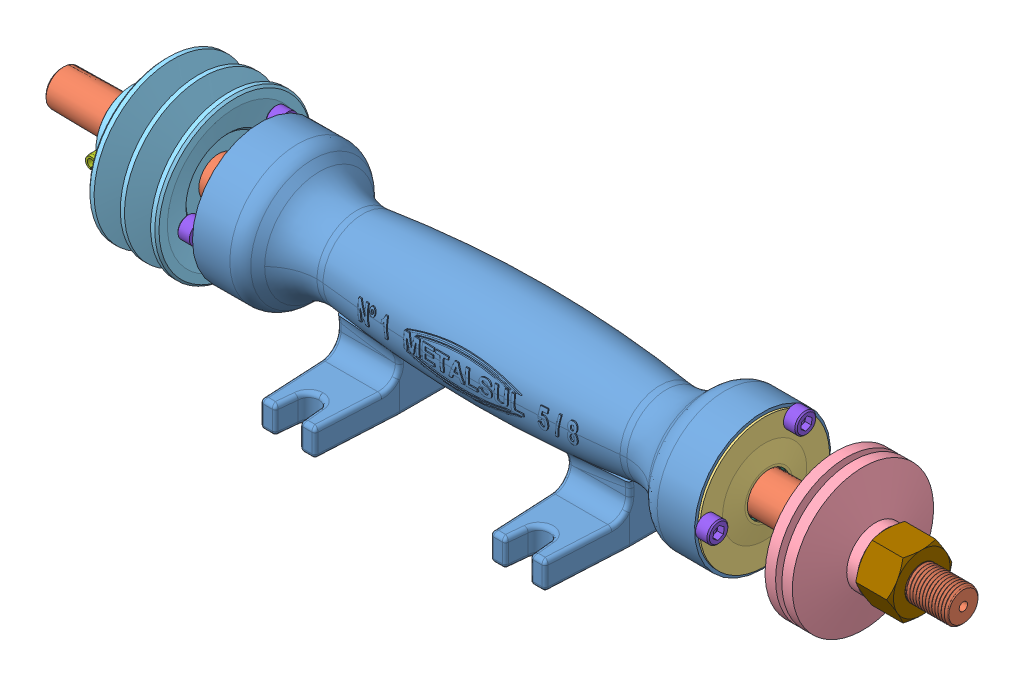
SolidWorks assembly Eixo Serra Circular 5-8 N1, configuration Valor predeterminado. Lengths in mm.
Overall size (431.24 80.12 104.06).
17 component instances, 9 part files, 0 mates.
Components (placement in the parent):
- Base Principal-1: Base Principal [Valor predeterminado] at origin size (240 75.12 104.06)
- Eixo Principal-1: Eixo Principal [Valor predeterminado] at (9 0 0) size (431.24 28 28)
- Tampa Rolamento-1: Tampa Rolamento [Valor predeterminado] at (121.5 0 0) x (0 0 1) z (-1 0 0) size (62 62 3)
- Tampa Rolamento-2: Tampa Rolamento [Valor predeterminado] at (-121.5 0 0) x (0 0 1) z (1 0 0) size (62 62 3)
- Suporte Principal-1: Suporte Principal [Valor predeterminado] at (152 0 0) size (16 67.5 67.5)
- Suporte Principal-2: Suporte Principal [Valor predeterminado] at (171 0 0) x (-1 0 0) z (0 0 -1) size (16 67.5 67.5)
- Polia Correa Dupla-1: Polia Correa Dupla [Valor predeterminado] at (-157 0 0) size (50 75 75)
- angular contact ball bearing_68_skf_SKF - 7204 BE - 10,DE,AC,10_68-1: angular contact ball bearing_68_skf_SKF - 7204 BE - 10,DE,AC,10_68 [Valor predeterminado] at (113 0 0) size (14 47 47)
- angular contact ball bearing_68_skf_SKF - 7204 BE - 10,DE,AC,10_68-2: angular contact ball bearing_68_skf_SKF - 7204 BE - 10,DE,AC,10_68 [Valor predeterminado] at (-113 0 0) size (14 47 47)
- spring pin slotted_hd_din_Spring Pin ISO 8752 - 6 x 50 - N - St-1: spring pin slotted_hd_din_Spring Pin ISO 8752 - 6 x 50 - N - St [Valor predeterminado] at (-176 0 25) x (0 0 -1) z (0 -1 0) size (50 6 5.99)
- socket head cap screw_am_B18.3.1M - 6 x 1.0 x 16 Hex SHCS -- 16SHX-1: socket head cap screw_am_B18.3.1M - 6 x 1.0 x 16 Hex SHCS -- 16SHX [Valor predeterminado] at (127 24.2487 -14) x (-1 0 0) z (0 0.924225 0.381849) size (22 10 10)
- socket head cap screw_am_B18.3.1M - 6 x 1.0 x 16 Hex SHCS -- 16SHX-2: socket head cap screw_am_B18.3.1M - 6 x 1.0 x 16 Hex SHCS -- 16SHX [Valor predeterminado] at (127 0 28) x (-1 0 0) z (0 0.924225 0.381849) size (22 10 10)
- socket head cap screw_am_B18.3.1M - 6 x 1.0 x 16 Hex SHCS -- 16SHX-3: socket head cap screw_am_B18.3.1M - 6 x 1.0 x 16 Hex SHCS -- 16SHX [Valor predeterminado] at (127 -24.2487 -14) x (-1 0 0) z (0 0.924225 0.381849) size (22 10 10)
- socket head cap screw_am_B18.3.1M - 6 x 1.0 x 16 Hex SHCS -- 16SHX-4: socket head cap screw_am_B18.3.1M - 6 x 1.0 x 16 Hex SHCS -- 16SHX [Valor predeterminado] at (-127 24.2487 -14) size (22 10 10)
- socket head cap screw_am_B18.3.1M - 6 x 1.0 x 16 Hex SHCS -- 16SHX-5: socket head cap screw_am_B18.3.1M - 6 x 1.0 x 16 Hex SHCS -- 16SHX [Valor predeterminado] at (-127 0 28) size (22 10 10)
- socket head cap screw_am_B18.3.1M - 6 x 1.0 x 16 Hex SHCS -- 16SHX-6: socket head cap screw_am_B18.3.1M - 6 x 1.0 x 16 Hex SHCS -- 16SHX [Valor predeterminado] at (-127 -24.2487 -14) size (22 10 10)
- hex nut heavy_am_B18.2.4.6M - Heavy hex nut,  M16 x 2 --D-S-1: hex nut heavy_am_B18.2.4.6M - Heavy hex nut,  M16 x 2 --D-S [Valor predeterminado] at (179 0 0) x (0 1 0) z (-1 0 0) size (27 31.18 17.1)
